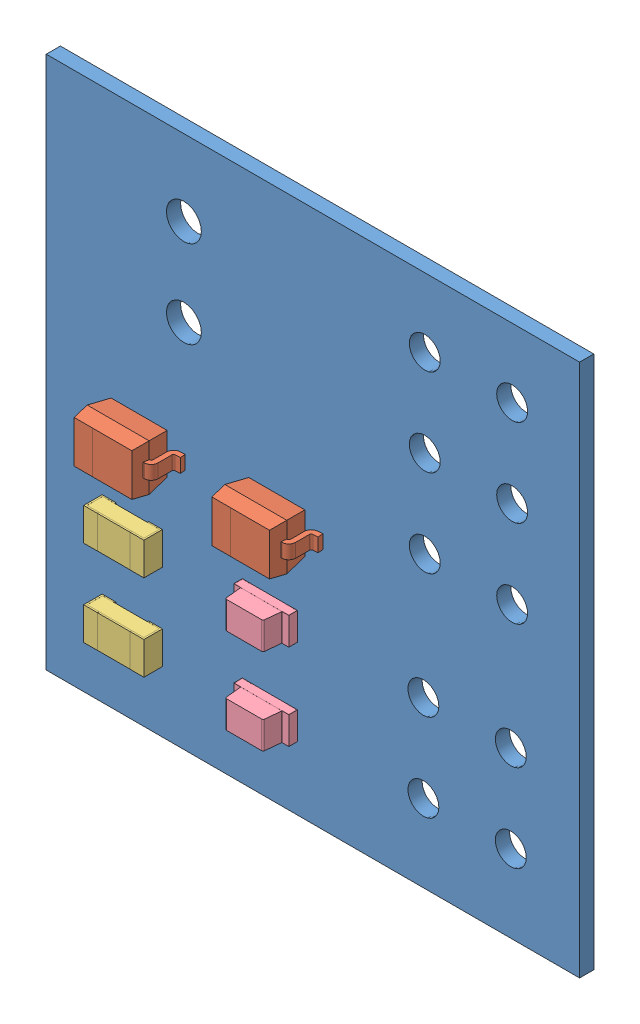
SolidWorks assembly tinyFan, configuration Default. Lengths in mm.
Overall size (15.5 15.5 3.25).
15 component instances, 5 part files, 0 mates.
Components (placement in the parent):
- Board-1: Board [Default] at (0 0 -0.4115) size (15.5 15.5 0.41)
- D2-1: D2 [Default] at origin size (2.6 1.35 1.1)
  - SOD323-1: SOD323 [Default] at (6.7499 7.2499 0) size (2.6 1.35 1.1)
- D1-1: D1 [Default] at origin size (2.6 1.35 1.1)
  - SOD323-1: SOD323 [Default] at (2.7499 7.2499 0) size (2.6 1.35 1.1)
- R2-1: R2 [Default] at origin size (1.75 0.95 0.55)
  - RES_0603_(1608_metric)-1: RES_0603_(1608_metric) [Default] at (2.5 2.2501 -0.013) size (1.75 0.95 0.55)
- R1-1: R1 [Default] at origin size (1.75 0.95 0.55)
  - RES_0603_(1608_metric)-1: RES_0603_(1608_metric) [Default] at (2.5 4.7501 -0.013) size (1.75 0.95 0.55)
- LED2-1: LED2 [Default] at origin size (1.6 0.8 0.75)
  - LED_0603_APT1608_RED-1: LED_0603_APT1608_RED [Default] at (6.5001 2.2501 0) x (1 0 0) z (0 0 1) size (1.6 0.8 0.75)
- LED1-1: LED1 [Default] at origin size (1.6 0.8 0.75)
  - LED_0603_APT1608_RED-1: LED_0603_APT1608_RED [Default] at (6.5001 4.7501 0) x (1 0 0) z (0 0 1) size (1.6 0.8 0.75)
- Q1-1: Q1 [Default] at origin size (6 4.9 1.75)
  - SOIC-8-1: SOIC-8 [Default] at (4.4999 5.0001 -0.4013) x (0 -1 0) z (0 0 -1) size (4.9 6 1.75)
